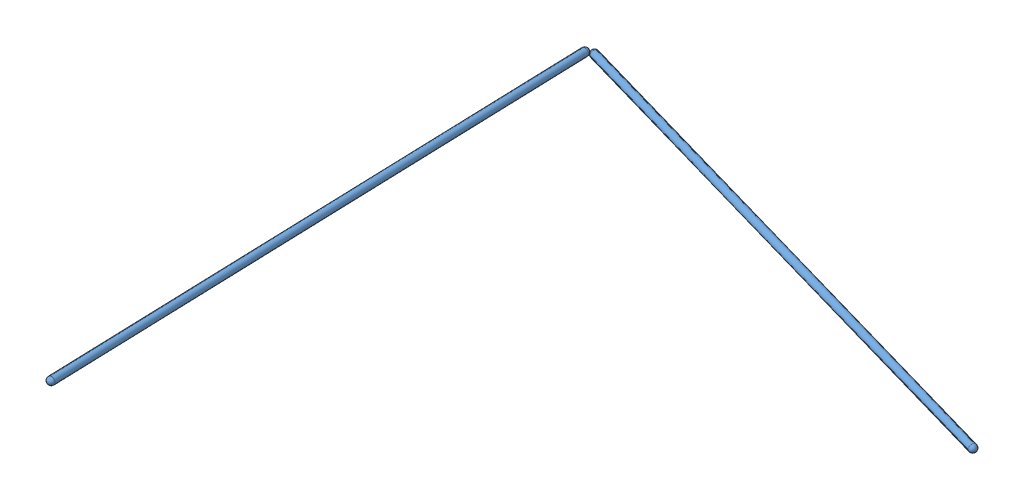
SolidWorks assembly dome_4v_model_1_D_triangle, configuration Default. Lengths in mm.
Overall size (1396 19.05 1440.45).
2 component instances, 1 part files, 1 mates.
Components (placement in the parent):
- dome_4v_D_model_1-1: dome_4v_D_model_1 [Default] at (581.8379 1152.8382 1163.7838) x (0.999474 0 -0.032432) z (0.032432 0 0.999474) size (19.05 19.05 1430.77)
- dome_4v_D_model_1-2: dome_4v_D_model_1 [Default] at (599.19 1152.8382 1155.9222) x (0.275637 0 -0.961262) z (0.961262 0 0.275637) size (19.05 19.05 1430.77)
Mates (geometry in assembly coordinates):
- Tangent1: tangent: sphere of dome_4v_D_model_1-1; sphere of dome_4v_D_model_1-2
